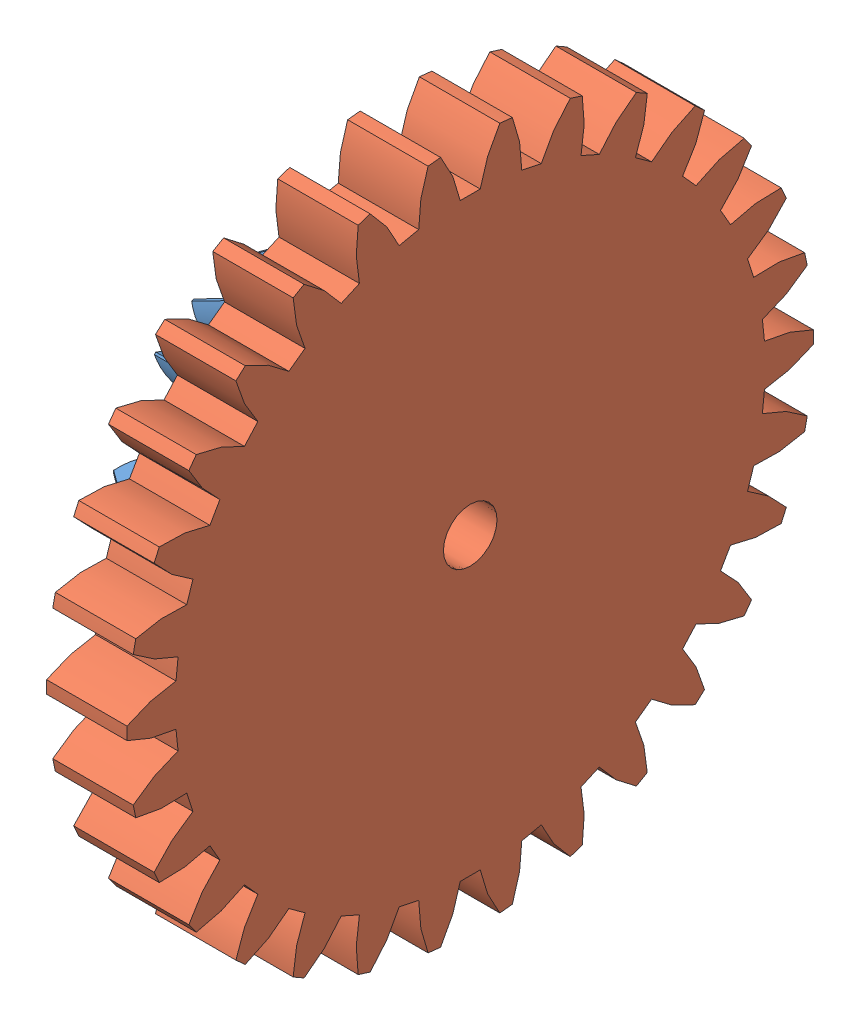
SolidWorks assembly ARMUS-REV2-100, configuration Défaut. Lengths in mm.
Overall size (50.86 161.95 162.56).
2 component instances, 2 part files, 4 mates.
Components (placement in the parent):
- straight bevel pinion_ai-4: straight bevel pinion_ai [Inch - Straight bevel pinion 6DP20PT 30GT 20PA 0.75FW ---20O4H3MD0.5N] at (-9.9279 0 0) x (-1 0 0) z (0 0 -1) size (31.81 92.88 92.88)
- spur gear_ai-3: spur gear_ai [Inch - Spur gear 5DP 30T 20PA .75FW ---S30N3.0H2.0L0.5N] at origin size (19.05 161.95 162.56)
Mates (geometry in assembly coordinates):
- Coincident34: coincident anti-aligned: plane of straight bevel pinion_ai-4 through (0 0 0) normal (1 0 0); plane of spur gear_ai-3 through (0 0 0) normal (-1 0 0)
- Coincident35: coincident anti-aligned: plane of straight bevel pinion_ai-4 through (-9.9279 0 0) normal (0 0 -1); plane of spur gear_ai-3 through (0 0 0) normal (0 0 1)
- Coincident36: coordinate: point of spur gear_ai-3
- Concentric1: concentric anti-aligned: cylinder of straight bevel pinion_ai-4 through (-86.1279 0 0) axis (1 0 0) radius 6.35; cylinder of spur gear_ai-3 through (50.8001 0 0) axis (-1 0 0) radius 6.35
